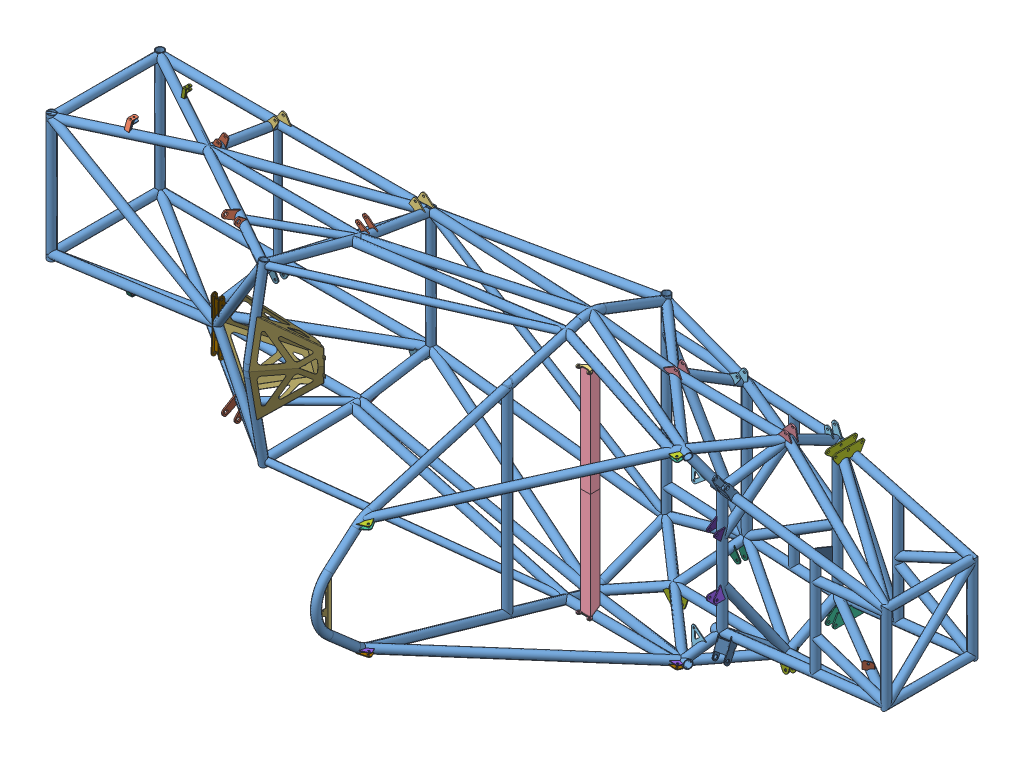
SolidWorks assembly PUTM-F-FR-Assembly, configuration Domyślna. Lengths in mm.
Overall size (2605 784.33 1125).
62 component instances, 43 part files, 3 mates.
Components (placement in the parent):
- PUTM-F-FR-FR-Frame-1: PUTM-F-FR-FR-Frame [Domyślna<As Machined>] x (-1 0 0) z (0 0 1) size (2605 784.33 1125)
- PUTM-F-FR-MT-Assembly-2: PUTM-F-FR-MT-Assembly [Domyślna] at origin size (2284.3 696.88 1074.85)
  - PUTM-F-FR-MT-Wishbone-FLU-1: PUTM-F-FR-MT-Wishbone-FLU [Domyślna] at origin size (500.39 51.83 39.02)
  - PUTM-F-FR-MT-Wishbone-FLB-1: PUTM-F-FR-MT-Wishbone-FLB [Domyślna] at origin size (501.86 44.47 30.4)
  - PUTM-F-FR-MT-Wishbone-RLU-1: PUTM-F-FR-MT-Wishbone-RLU [Domyślna] at origin size (400.51 61.79 44.73)
  - PUTM-F-FR-MT-Wishbone-RLB-1: PUTM-F-FR-MT-Wishbone-RLB [Domyślna] at origin size (335.58 43.04 28.5)
  - PUTM-F-FR-MT-L-DynamicToeMounting-1: PUTM-F-FR-MT-L-DynamicToeMounting [Domyślna] at origin size (29.34 479.49 99)
    - PUTM-F-FR-MT-L-Mounting-1: PUTM-F-FR-MT-L-Mounting [Domyślna] at origin size (29.34 37.4 99)
    - PUTM-F-FR-MT-R-Mounting-1: PUTM-F-FR-MT-R-Mounting [Domyślna] at origin size (29.34 37.4 99)
  - PUTM-F-FR-MT-DampersMountings-1: PUTM-F-FR-MT-DampersMountings [Domyślna] at origin size (1455.47 121.72 162.6)
    - PUTM-F-FR-MT-LR-DamperMounting-1: PUTM-F-FR-MT-LR-DamperMounting [Domyślna] at origin size (28.79 63.22 33.85)
    - PUTM-F-FR-MT-LF-DamperMounting-1: PUTM-F-FR-MT-LF-DamperMounting [Domyślna<Obrobiona>] at origin size (27.17 85.78 29.27)
  - PUTM-F-FR-MT-RockersMountings-1: PUTM-F-FR-MT-RockersMountings [Domyślna] at origin size (1503.94 95.64 129.43)
    - PUTM-F-FR-MT-LR-RockerMounting-1: PUTM-F-FR-MT-LR-RockerMounting [Domyślna<Obrobiona>] at origin size (51.09 67.79 52.23)
    - PUTM-F-FR-MT-LF-RockerMounting-1: PUTM-F-FR-MT-LF-RockerMounting [Domyślna] at origin size (43 43.34 59.01)
  - PUTM-F-FR-MT-TSAL-Mounting-1: PUTM-F-FR-MT-TSAL-Mounting [Domyślna] at origin size (12 190.3 31)
  - LustroPUTM-F-FR-MT-Wishbone-FLU-2: LustroPUTM-F-FR-MT-Wishbone-FLU [Domyślna] x (1 0 0) z (0 0 -1) size (500.39 51.83 39.02)
  - LustroPUTM-F-FR-MT-Wishbone-FLB-2: LustroPUTM-F-FR-MT-Wishbone-FLB [Domyślna] x (1 0 0) z (0 0 -1) size (501.81 44.47 30.4)
  - LustroPUTM-F-FR-MT-Wishbone-RLB-2: LustroPUTM-F-FR-MT-Wishbone-RLB [Domyślna] x (1 0 0) z (0 0 -1) size (335.52 43.04 28.49)
  - LustroPUTM-F-FR-MT-Wishbone-RLU-2: LustroPUTM-F-FR-MT-Wishbone-RLU [Domyślna] x (1 0 0) z (0 0 -1) size (400.51 61.79 44.73)
  - LustroPUTM-F-MT-DampersMountings-2: LustroPUTM-F-MT-DampersMountings [Domyślna] x (1 0 0) z (0 0 -1) size (1455.47 121.72 162.6)
    - LustroPUTM-F-FR-MT-LR-DamperMounting-1: LustroPUTM-F-FR-MT-LR-DamperMounting [Domyślna] at origin size (28.79 63.22 33.85)
    - LustroPUTM-F-FR-MT-LF-DamperMounting-1: LustroPUTM-F-FR-MT-LF-DamperMounting [Domyślna<Obrobiona>] at origin size (27.17 85.78 29.27)
  - LustroPUTM-F-MT-RockersMountings-2: LustroPUTM-F-MT-RockersMountings [Domyślna] x (1 0 0) z (0 0 -1) size (1503.94 95.64 129.43)
    - LustroPUTM-F-FR-MT-LR-RockerMounting-1: LustroPUTM-F-FR-MT-LR-RockerMounting [Domyślna<Obrobiona>] at origin size (51.09 67.79 52.23)
    - LustroPUTM-F-FR-MT-LF-RockerMounting-1: LustroPUTM-F-FR-MT-LF-RockerMounting [Domyślna] at origin size (43 43.34 59.01)
  - PUTM-F-FR-MT-Box-Mountings-1: PUTM-F-FR-MT-Box-Mountings [Domyślna] at origin size (401.55 696.88 50.33)
    - PUTM-F-FR-MT-Box-Bar-Fixing-1: PUTM-F-FR-MT-Box-Bar-Fixing [Domyślna] at origin size (46 2 24.39)
    - PUTM-F-FR-MT-Box-Mounting-Bar-1: PUTM-F-FR-MT-Box-Mounting-Bar [Domyślna<Obrobiona>] at origin size (46 696.88 50.33)
    - PUTM-F-FR-MT-Rear-Box-Fixing-1: PUTM-F-FR-MT-Rear-Box-Fixing [Domyślna] at origin size (46.55 75.76 2)
  - PUTM-F-FR-MT-Aero-FW-Mounting-1: PUTM-F-FR-MT-Aero-FW-Mounting [Domyślna] at origin
    - PUTM-F-FR-MT-Aero-FW-Kinematics-1: PUTM-F-FR-MT-Aero-FW-Kinematics [Domyślna] at origin
  - PUTM-F-FR-MT-Aero-RW-Mountings-1: PUTM-F-FR-MT-Aero-RW-Mountings [Domyślna] at origin size (440.97 126.76 591.66)
    - PUTM-F-FR-MT-Aero-RW-Inside-Kinematics-1: PUTM-F-FR-MT-Aero-RW-Inside-Kinematics [Domyślna] at (0 365.9457 71.1326) x (1 0 0) z (0 0.981627 0.190809)
    - PUTM-F-FR-MT-Aero-RW-Inside-Mounting-1: PUTM-F-FR-MT-Aero-RW-Inside-Mounting [Domyślna] at origin size (432.93 116.74 590.82)
    - PUTM-F-FR-MT-Aero-RW-Outside-Mounting-1: PUTM-F-FR-MT-Aero-RW-Outside-Mounting [Domyślna] at origin size (440.97 116.74 590.82)
  - Left sidePUTM-F-FR-MT-Aero-RW-Mountings-2: Left sidePUTM-F-FR-MT-Aero-RW-Mountings [Domyślna] x (1 0 0) z (0 0 -1) size (440.97 126.76 591.66)
    - PUTM-F-FR-MT-Aero-RW-Inside-Kinematics-1: PUTM-F-FR-MT-Aero-RW-Inside-Kinematics [Domyślna] at (0 365.9457 -71.1326) x (1 0 0) z (0 -0.981627 0.190809)
    - Left sidePUTM-F-FR-MT-Aero-RW-Inside-Mounting-1: Left sidePUTM-F-FR-MT-Aero-RW-Inside-Mounting [Domyślna] at origin size (432.93 116.74 590.82)
    - Left sidePUTM-F-FR-MT-Aero-RW-Outside-Mounting-1: Left sidePUTM-F-FR-MT-Aero-RW-Outside-Mounting [Domyślna] at origin size (440.97 116.74 590.82)
  - PUTM-F-FR-MT-Chain_cover_mounting-1: PUTM-F-FR-MT-Chain_cover_mounting [Domyślna] x (-1 0 0) z (0 0 1) size (354.59 79 209.73)
    - PUTM-F-FR-MT-Front-1: PUTM-F-FR-MT-Front [Domyślna] at (-1058.5579 102.45 732.9475) x (0 -1 0) z (0.822156 0 -0.569262) size (55 45 2)
    - PUTM-F-FR-MT-Rear-1: PUTM-F-FR-MT-Rear [Domyślna] at (-452.0433 102.45 956.2533) x (-0.904074 0 -0.427377) z (-0.427377 0 0.904074) size (30 24 2)
  - PUTM-F-FR-MT-SteeringColumnMt-1: PUTM-F-FR-MT-SteeringColumnMt [Domyślna] at origin size (294.47 282.28 155.41)
  - PUTM-F-FR-MT-Aero-FW- Upper-Mounting-1: PUTM-F-FR-MT-Aero-FW- Upper-Mounting [Domyślna] at (-493.4808 -253.8581 365.2905) x (0 -1 0) z (1 0 0) size (27.7 32.64 15.07)
    - PUTM-F-FR-MT-Aero-FW- Upper-Mounting-Part 3-1: PUTM-F-FR-MT-Aero-FW- Upper-Mounting-Part 3 [Domyślna] at (-15.8581 365.2905 33.8829) size (12 2 15)
    - PUTM-F-FR-MT-Aero-FW- Upper-Mounting.Part2-2: PUTM-F-FR-MT-Aero-FW- Upper-Mounting.Part2 [Domyślna] at (-15.8575 365.2905 33.8357) size (15.83 26.97 15)
    - PUTM-F-FR-MT-Aero-FW- Upper-Mounting-Part1-1: PUTM-F-FR-MT-Aero-FW- Upper-Mounting-Part1 [Domyślna] at (-15.8581 365.2387 33.9051) size (27.7 32.59 15)
  - PUTM-F-FR-MT-Aero-FW-Lower-Mounting-1: PUTM-F-FR-MT-Aero-FW-Lower-Mounting [Domyślna] at (-491.9371 -233.3344 199.7429) x (0 -1 0) z (1 0 0) size (25.16 25.95 10)
    - PUTM-F-FR-MT-Aero-FW-Lower-Mounting-Part2^PUTM-F-FR-MT-Aero-FW-Lower-Mounting-1: PUTM-F-FR-MT-Aero-FW-Lower-Mounting-Part2^PUTM-F-FR-MT-Aero-FW-Lower-Mounting [Domyślna] at (4.6656 195.4734 30.7929) size (25.16 25.95 10) (virtual)
    - PUTM-F-FR-MT-Aero-FW-Lower-Mounting-Part2-1: PUTM-F-FR-MT-Aero-FW-Lower-Mounting-Part2 [Domyślna] at (4.6517 195.426 30.7923) size (12 2 6)
  - LustroPUTM-F-FR-MT-Aero-FW- Upper-Mounting-2: LustroPUTM-F-FR-MT-Aero-FW- Upper-Mounting [Domyślna] at (-493.4808 253.8581 365.2905) x (0 1 0) z (-1 0 0) size (27.7 32.64 15.07)
    - LustroPUTM-F-FR-MT-Aero-FW- Upper-Mounting-Part 3-1: LustroPUTM-F-FR-MT-Aero-FW- Upper-Mounting-Part 3 [Domyślna] at (-15.8581 365.2905 -33.8829) size (12 2 15)
    - LustroPUTM-F-FR-MT-Aero-FW- Upper-Mounting.Part2-1: LustroPUTM-F-FR-MT-Aero-FW- Upper-Mounting.Part2 [Domyślna] at (-15.8575 365.2905 -33.8357) size (15.83 26.97 15)
    - LustroPUTM-F-FR-MT-Aero-FW- Upper-Mounting-Part1-1: LustroPUTM-F-FR-MT-Aero-FW- Upper-Mounting-Part1 [Domyślna] at (-15.8581 365.2387 -33.9051) size (27.7 32.59 15)
  - PUTM-F-FR-MT-Aero-FW-Lower-Mounting-2: PUTM-F-FR-MT-Aero-FW-Lower-Mounting [Domyślna] at (-440.3513 233.3344 199.7429) x (0 1 0) z (-1 0 0) size (25.16 25.95 10)
    - PUTM-F-FR-MT-Aero-FW-Lower-Mounting-Part2^PUTM-F-FR-MT-Aero-FW-Lower-Mounting-1: PUTM-F-FR-MT-Aero-FW-Lower-Mounting-Part2^PUTM-F-FR-MT-Aero-FW-Lower-Mounting [Domyślna] at (4.6656 195.4734 30.7929) size (25.16 25.95 10) (virtual)
    - PUTM-F-FR-MT-Aero-FW-Lower-Mounting-Part2-1: PUTM-F-FR-MT-Aero-FW-Lower-Mounting-Part2 [Domyślna] at (4.6517 195.426 30.7923) size (12 2 6)
  - LustroPUTM-F-FR-MT-Box-Mountings-4: LustroPUTM-F-FR-MT-Box-Mountings [Domyślna] x (1 0 0) z (0 0 -1) size (401.55 336.44 41.1)
    - LustroPUTM-F-FR-MT-Box-Bar-Fixing-1: LustroPUTM-F-FR-MT-Box-Bar-Fixing [Domyślna] at origin size (46 2 24.39)
    - LustroPUTM-F-FR-MT-Box-Mounting-Bar-1: LustroPUTM-F-FR-MT-Box-Mounting-Bar [Domyślna<Obrobiona>] at origin size (46 334.44 41.1)
    - LustroPUTM-F-FR-MT-Rear-Box-Fixing-1: LustroPUTM-F-FR-MT-Rear-Box-Fixing [Domyślna] at origin size (46.55 75.76 2)
Mates (geometry in assembly coordinates):
- Wspólnie2: coincident aligned: plane of PUTM-F-FR-FR-Frame-1 through (0 0 0) normal (0 0 1)
- Wspólnie3: coincident anti-aligned: plane of PUTM-F-FR-FR-Frame-1 through (0 0 0) normal (0 -1 0)
- Wspólnie4: coincident anti-aligned: plane of PUTM-F-FR-FR-Frame-1 through (0 0 0) normal (-1 0 0)
